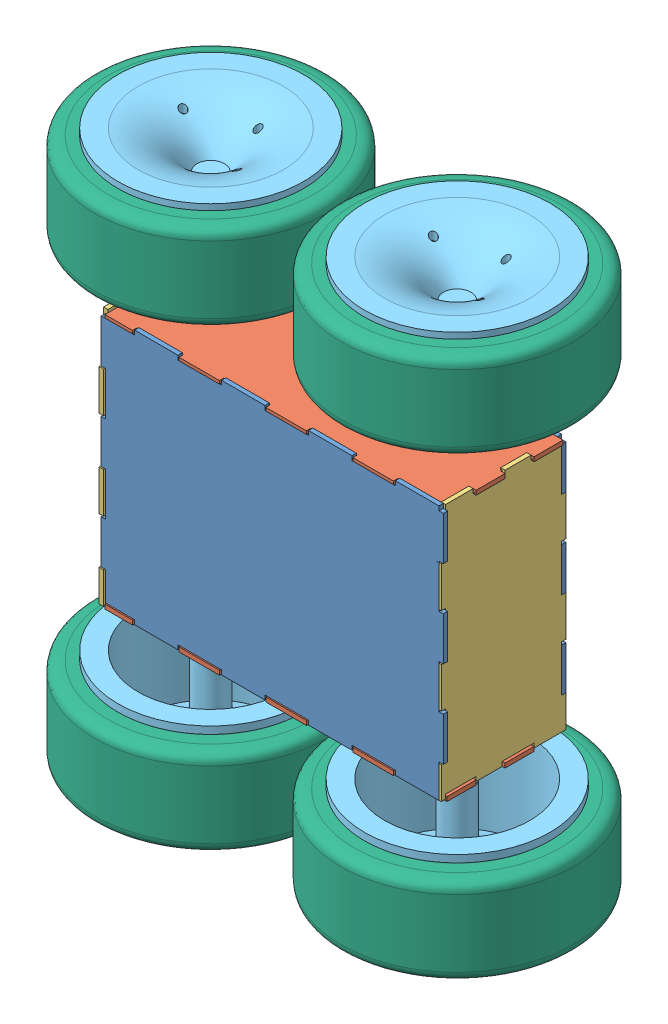
SolidWorks assembly Assemblage robot, configuration Défaut. Lengths in mm.
Overall size (404.1 390.21 416.4).
21 component instances, 6 part files, 8 mates.
Components (placement in the parent):
- Assemblage2-1: Assemblage2 [Défaut] at (16.7802 -27.4778 11.8562) size (237.4 318.21 86)
  - Pièce2-1: Pièce2 [Défaut] at (-43.6549 26.5159 234.5) size (236 176 3)
  - Pièce 3-1: Pièce 3 [Défaut] at (101.8822 -81.5611 317.5) x (-1 0 0) z (0 -1 0) size (236 86 3)
  - Pièce 3-3: Pièce 3 [Défaut] at (101.8822 88.4389 237.5) x (-1 0 0) z (0 1 0) size (236 86 3)
  - Pièce2-2: Pièce2 [Défaut] at (-42.2504 27.4093 317.5) size (236 176 3)
  - Pièce5-1: Pièce5 [Défaut] at (-129.1178 44.8499 260.0256) x (0 -1 0) z (-1 0 0) size (176 86 3)
  - Pièce5-2: Pièce5 [Défaut] at (103.8822 44.8499 260.0256) x (0 -1 0) z (-1 0 0) size (176 86 3)
  - Barre de roue-2: Barre de roue [Défaut] at (71.8822 -141.4395 277.5) x (0.910463 0 -0.413591) z (0 1 0) size (10 10 310)
  - Barre de roue-3: Barre de roue [Défaut] at (-98.1178 160.3543 277.5) x (0.057472 0 0.998347) z (0 -1 0) size (10 10 310)
- roue bien precise-1: roue bien precise [Défaut] at (206.823 142.8882 338.6299) x (0 1 0) z (-0.930065 0 -0.367394) size (70 217.98 217.98)
  - roue2 graine-1: roue2 graine [Défaut] at (-0.8054 2.4163 128) size (70 128 128)
  - roue bien bien prcise-1: roue bien bien prcise [Défaut] at (-23.1721 2.4163 128) x (0 0.870871 -0.491512) z (1 0 0) size (160 160 60.01)
- roue bien precise-2: roue bien precise [Défaut] at (40.0756 134.6819 329.9599) x (0 1 0) z (-0.954189 0 -0.299204) size (70 217.98 217.98)
  - roue2 graine-1: roue2 graine [Défaut] at (-0.8054 2.4163 128) size (70 128 128)
  - roue bien bien prcise-1: roue bien bien prcise [Défaut] at (-23.1721 2.4163 128) x (0 0.870871 -0.491512) z (1 0 0) size (160 160 60.01)
- roue bien precise-3: roue bien precise [Défaut] at (191.5798 -170.7227 213.2126) x (0 -1 0) z (-0.814981 0 0.579487) size (70 217.98 217.98)
  - roue2 graine-1: roue2 graine [Défaut] at (-0.8054 2.4163 128) size (70 128 128)
  - roue bien bien prcise-1: roue bien bien prcise [Défaut] at (-23.1721 2.4163 128) x (0 0.870871 -0.491512) z (1 0 0) size (160 160 60.01)
- roue bien precise-4: roue bien precise [Défaut] at (46.6624 -178.9289 286.94) x (0 -1 0) z (-1 0 0) size (70 217.98 217.98)
  - roue2 graine-1: roue2 graine [Défaut] at (-0.8054 2.4163 128) size (70 128 128)
  - roue bien bien prcise-1: roue bien bien prcise [Défaut] at (-23.1721 2.4163 128) x (0 0.870871 -0.491512) z (1 0 0) size (160 160 60.01)
Mates (geometry in assembly coordinates):
- Coaxiale1: concentric aligned: cylinder of Assemblage2-1/Barre de roue-2 through (88.6624 141.0827 289.3562) axis (0 -1 0) radius 5; cylinder of roue bien precise-1/roue2 graine-1 through (88.6624 151.0827 289.3562) axis (0 -1 0) radius 5
- Coïncidente1: coincident anti-aligned: plane of Assemblage2-1/Barre de roue-2 through (88.6624 141.0827 289.3562) normal (0 1 0); plane of roue bien precise-1/roue2 graine-1 through (88.6624 141.0827 289.3562) normal (0 -1 0)
- Coïncidente2: coincident anti-aligned: plane of Assemblage2-1/Barre de roue-3 through (-81.3376 -177.1235 289.3562) normal (0 -1 0); plane of roue bien precise-4/roue2 graine-1 through (-81.3376 -177.1235 289.3562) normal (0 1 0)
- Coaxiale2: concentric aligned: cylinder of Assemblage2-1/Barre de roue-3 through (-81.3376 -177.1235 289.3562) axis (0 1 0) radius 5; cylinder of roue bien precise-4/roue2 graine-1 through (-81.3376 -187.1235 289.3562) axis (0 1 0) radius 5
- Coïncidente3: coincident aligned: circle of Assemblage2-1/Barre de roue-3; plane of roue bien precise-2/roue2 graine-1 through (-81.3376 132.8765 289.3562) normal (0 -1 0)
- Coaxiale3: concentric anti-aligned: cylinder of Assemblage2-1/Barre de roue-3 through (-81.3376 -177.1235 289.3562) axis (0 1 0) radius 5; cylinder of roue bien precise-2/roue2 graine-1 through (-81.3376 142.8765 289.3562) axis (0 -1 0) radius 5
- Coïncidente4: coincident anti-aligned: plane of Assemblage2-1/Barre de roue-2 through (88.6624 -168.9173 289.3562) normal (0 -1 0); plane of roue bien precise-3/roue2 graine-1 through (88.6624 -168.9173 289.3562) normal (0 1 0)
- Coaxiale4: concentric anti-aligned: cylinder of Assemblage2-1/Barre de roue-2 through (88.6624 141.0827 289.3562) axis (0 -1 0) radius 5; cylinder of roue bien precise-3/roue2 graine-1 through (88.6624 -178.9173 289.3562) axis (0 1 0) radius 5
